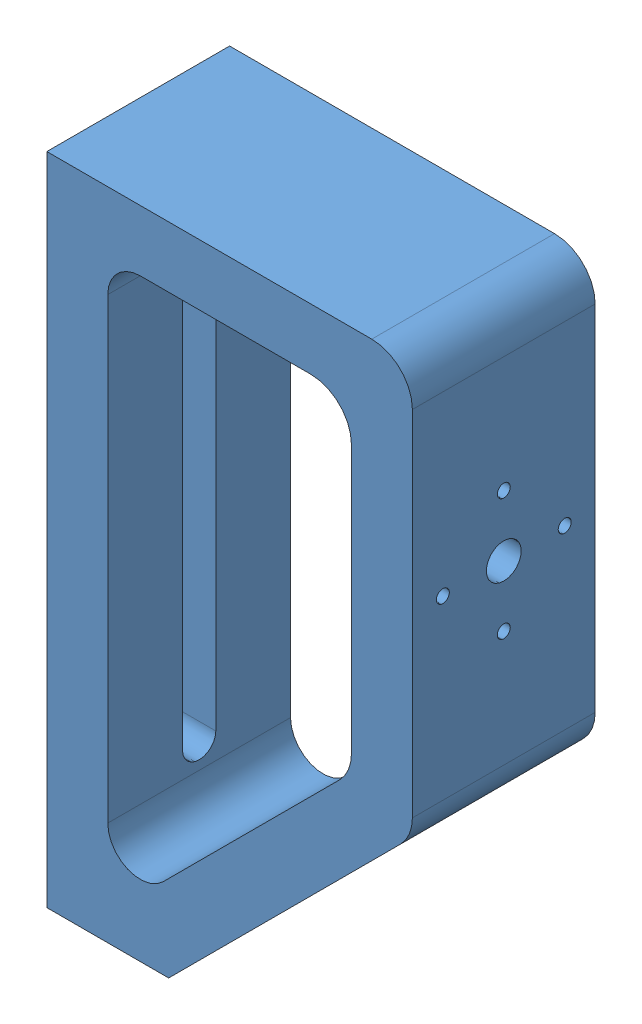
SolidWorks assembly Stand_Rail_Mount_Assembly_P, configuration Default. Lengths in mm.
Overall size (90 161.21 45).
5 component instances, 2 part files, 12 mates.
Components (placement in the parent):
- Stand_Rail_Mount_P-1: Stand_Rail_Mount_P [Default] at (11.6506 -33.7626 108.0555) size (90 161.21 45)
- M3 x 0.5 Hex Nut-1: M3 x 0.5 Hex Nut [90592A085] at (88.9506 103.9151 115.5555) x (0 -0.866025 -0.5) z (0 0.5 -0.866025) size (5.5 2.98 6.35)
- M3 x 0.5 Hex Nut-2: M3 x 0.5 Hex Nut [90592A085] at (88.9506 118.9151 130.5555) x (0 -1 0) z (0 0 -1) size (5.5 2.98 6.35)
- M3 x 0.5 Hex Nut-3: M3 x 0.5 Hex Nut [90592A085] at (88.9506 88.9151 130.5555) x (0 -1 0) z (0 0 -1) size (5.5 2.98 6.35)
- M3 x 0.5 Hex Nut-4: M3 x 0.5 Hex Nut [90592A085] at (88.9506 103.9151 145.5555) x (0 -0.866025 -0.5) z (0 0.5 -0.866025) size (5.5 2.98 6.35)
Mates (geometry in assembly coordinates):
- Concentric1: concentric: circle of Stand_Rail_Mount-1; circle of M3 x 0.5 Hex Nut-1
- Concentric2: concentric anti-aligned: circle of Stand_Rail_Mount-1; circle of M3 x 0.5 Hex Nut-2
- Concentric3: concentric: circle of Stand_Rail_Mount-1; circle of M3 x 0.5 Hex Nut-3
- Concentric4: concentric: circle of Stand_Rail_Mount-1; circle of M3 x 0.5 Hex Nut-4
- Parallel1: parallel: plane of Stand_Rail_Mount-1 through (90.1506 100.6242 115.5555) normal (0 0.866025 -0.5); plane of M3 x 0.5 Hex Nut-1 through (87.7506 100.7396 115.5555) normal (0 -0.866025 0.5)
- Parallel2: parallel anti-aligned: plane of Stand_Rail_Mount-1 through (90.1506 116.0651 132.2009) normal (0 0.5 -0.866025); plane of M3 x 0.5 Hex Nut-2 through (87.7506 116.1651 132.1432) normal (0 -0.5 0.866025)
- Parallel3: parallel: plane of Stand_Rail_Mount-1 through (90.1506 100.6242 145.5555) normal (0 0.866025 -0.5); plane of M3 x 0.5 Hex Nut-4 through (87.7506 100.7396 145.5555) normal (0 -0.866025 0.5)
- Parallel4: parallel: plane of Stand_Rail_Mount-1 through (90.1506 86.0651 132.2009) normal (0 0.5 -0.866025); plane of M3 x 0.5 Hex Nut-3 through (87.7506 86.1651 132.1432) normal (0 -0.5 0.866025)
- Coincident5: coincident anti-aligned: plane of Stand_Rail_Mount-1 through (90.1506 -33.7626 108.0555) normal (-1 0 0); plane of M3 x 0.5 Hex Nut-1 through (90.1506 105.5028 118.3055) normal (1 0 0)
- Coincident6: coincident anti-aligned: plane of Stand_Rail_Mount-1 through (90.1506 -33.7626 108.0555) normal (-1 0 0); plane of M3 x 0.5 Hex Nut-2 through (90.1506 121.6651 132.1432) normal (1 0 0)
- Coincident7: coincident anti-aligned: plane of Stand_Rail_Mount-1 through (90.1506 -33.7626 108.0555) normal (-1 0 0); plane of M3 x 0.5 Hex Nut-3 through (90.1506 91.6651 132.1432) normal (1 0 0)
- Coincident8: coincident anti-aligned: plane of Stand_Rail_Mount-1 through (90.1506 -33.7626 108.0555) normal (-1 0 0); plane of M3 x 0.5 Hex Nut-4 through (90.1506 105.5028 148.3055) normal (1 0 0)
